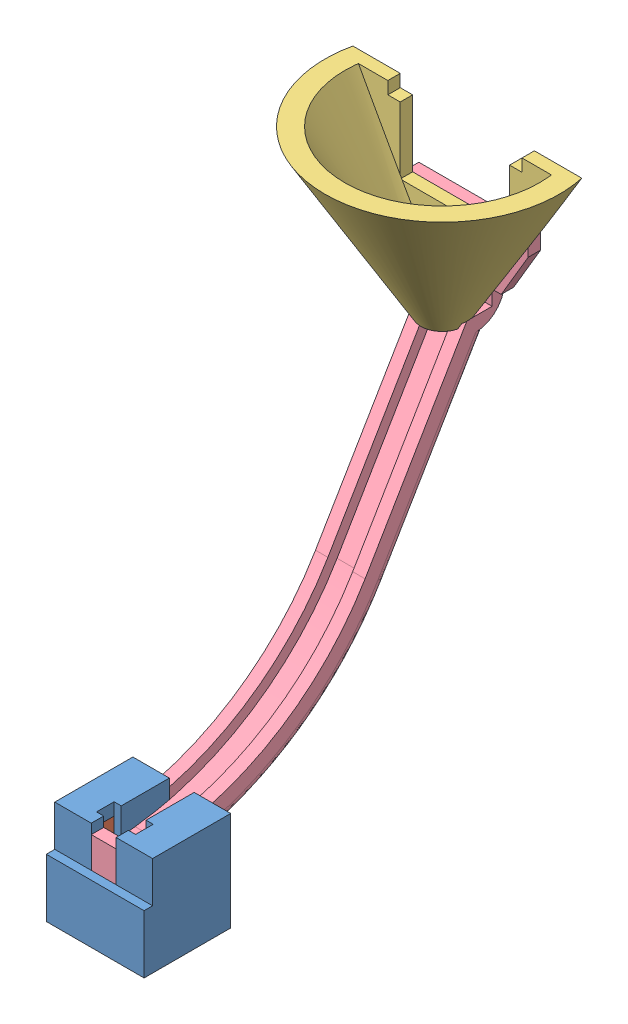
SolidWorks assembly funnelAssem_v3, configuration Default. Lengths in mm.
Overall size (60 154.23 118.85).
4 component instances, 4 part files, 9 mates.
Components (placement in the parent):
- photoInterrupterCase_v4-1: photoInterrupterCase_v4 [Default] at (-8.4963 -25.5024 12.0936) size (25.05 25.4 22.18)
- photoInterruptor_outline-1: photoInterruptor_outline [Default] at (-8.5463 -15.4774 18.9186) size (18.6 15.2 5)
- funnelCone_v3-1: funnelCone_v3 [Default] at (-8.4963 112.6126 -64.5814) x (-1 0 0) z (0 0 -1) size (60 74.98 60)
- funnelTrack_v5-1: funnelTrack_v5 [Default] at (-8.4963 112.6126 -64.5814) x (-1 0 0) z (0 0 -1) size (60 139.3 116.67)
Mates (geometry in assembly coordinates):
- Coincident1: coincident: plane of photoInterrupterCase_v4-1 through (-8.4963 -3.2774 18.9186) normal (0 -1 0); plane of photoInterruptor_outline-1 through (-13.5463 -3.2774 13.9186) normal (0 1 0)
- Coincident2: coincident: plane of photoInterrupterCase_v4-1 through (-17.8463 -25.5024 18.9186) normal (1 0 0); plane of photoInterruptor_outline-1 through (-17.8463 -3.2774 13.9186) normal (-1 0 0)
- Coincident3: coincident: plane of photoInterrupterCase_v4-1 through (-8.4963 -25.5024 18.9186) normal (0 0 -1); plane of photoInterruptor_outline-1 through (-8.5463 -15.4774 18.9186) normal (0 0 1)
- Coincident11: coincident: plane of funnelCone_v3-1 through (-48.5246 72.7177 -71.0214) normal (0 0 -1); plane of funnelTrack_v5-1 through (-37.3145 72.7177 -71.0214) normal (0 0 1)
- Coincident13: coincident: plane of photoInterrupterCase_v4-1 through (-17.8463 -0.1024 22.0936) normal (0 0 1); plane of funnelTrack_v5-1 through (-14.8463 -2.6399 22.0936) normal (0 0 1)
- Coincident14: coincident: plane of photoInterrupterCase_v4-1 through (-11.6713 -25.5024 22.0936) normal (1 0 0); plane of funnelTrack_v5-1 through (-11.6713 41.9948 2.0936) normal (-1 0 0)
- Coincident15: coincident: plane of photoInterrupterCase_v4-1 through (-8.4963 -10.5774 22.0936) normal (0 1 0); line of funnelTrack_v5-1 through (-11.6713 -10.5774 22.0936) axis (1 0 0)
- Coincident16: coincident: plane of funnelCone_v3-1 through (-0.8763 72.7177 -58.1414) normal (0 -1 0); plane of funnelTrack_v5-1 through (-49.1363 72.7177 -58.1414) normal (0 1 0)
- Coincident17: coincident: plane of funnelCone_v3-1 through (-8.4963 112.6126 -64.5814) normal (-1 0 0); plane of funnelTrack_v5-1 through (-8.4963 112.6126 -64.5814) normal (-1 0 0)
